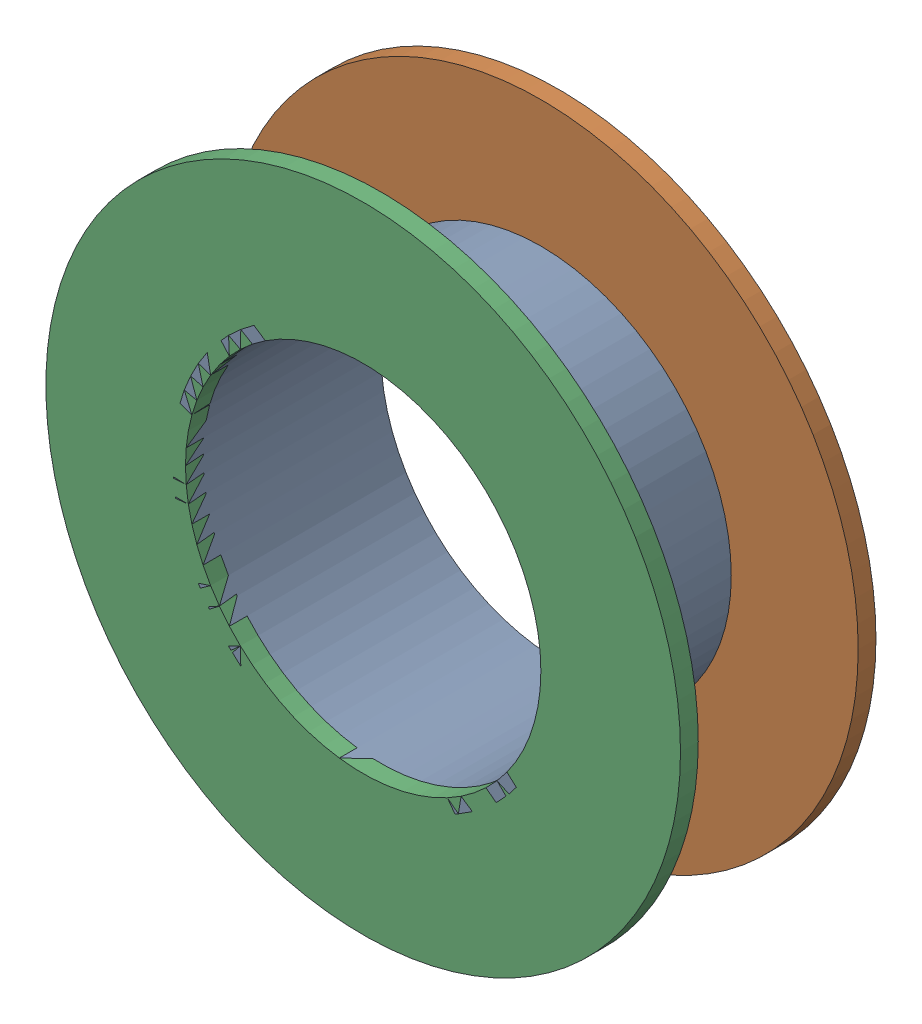
SolidWorks assembly Via (24.4mm,48.5mm) from Top Layer to Bottom Layer, configuration Predeterminado. Lengths in mm.
Overall size (1.27 1.27 0.39).
6 component instances, 2 part files, 0 mates.
Components (placement in the parent):
- Via Hole-1: Via Hole [Predeterminado] at (24.4 48.5 -0.4013) size (0.76 0.76 0.39)
  - Via Hole-Part-1-1: Via Hole-Part-1 [Predeterminado] at origin size (0.76 0.76 0.39)
- Via Top Layer-1: Via Top Layer [Predeterminado] at (24.4 48.5 -0.4013) size (1.27 1.27 0.04)
  - Via Top Layer-Part-1-1: Via Top Layer-Part-1 [Predeterminado] at origin size (1.27 1.27 0.04)
- Via Top Layer-2: Via Top Layer [Predeterminado] at (24.4 48.5 -0.0457) size (1.27 1.27 0.04)
  - Via Top Layer-Part-1-1: Via Top Layer-Part-1 [Predeterminado] at origin size (1.27 1.27 0.04)
